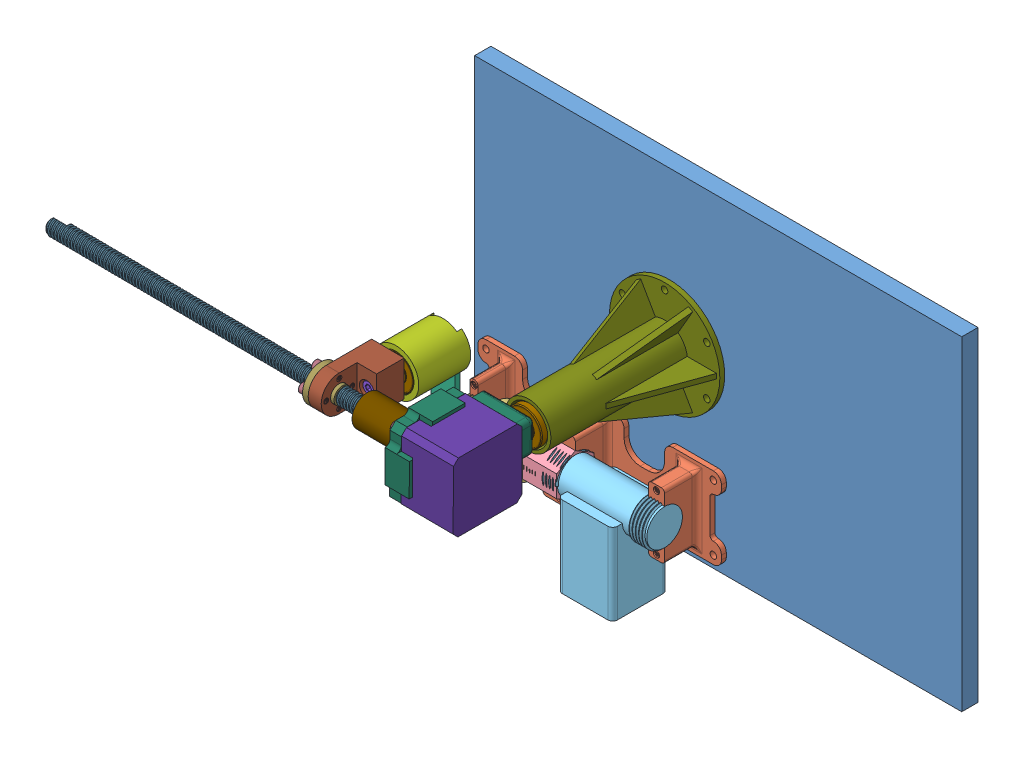
SolidWorks assembly ASM_gaz, configuration Défaut. Lengths in mm.
Overall size (432.05 220 163.25).
29 component instances, 18 part files, 83 mates.
Components (placement in the parent):
- socle-1: socle [Défaut] at (-258.099 -214.9208 295) size (300 200 10)
- support_gaz-1: support_gaz [Défaut] at (-178.099 -184.9208 305) size (150 50 23.02)
- valve-2: valve [Défaut] at (-186.099 -184.9208 328) x (0 1 0) z (0 0 1) size (30 53.36 57)
- raccord_male_male-1: raccord_male_male [Défaut] at (-194.099 -184.9208 328) x (0 -0.5 -0.866025) z (0 -0.866025 0.5) size (26.56 22.51 23)
- electro_vanne-1: electro_vanne [Défaut] at (-182.099 -184.9208 328) x (0 0 1) z (1 0 0) size (34 62.7 64.68)
- poignee_gaz-1: poignee_gaz [Défaut] at (-214.099 -193.9208 358) x (0 1 0) z (1 0 0) size (95 18 15)
- fix_poignee-1: fix_poignee [Défaut] at (-206.599 -107.9208 373) x (1 0 0) z (0 -1 0) size (28.2 32 28.2)
- M4_10-1: M4_10 [Défaut] at (-206.599 -107.9208 369) x (-0.866025 -0.5 0) z (-0.5 0.866025 0) size (7 14.03 7)
- roulement-1: roulement [Défaut] at (-206.599 -107.9208 401.5) x (0 0 -1) z (0.849779 -0.527139 0) size (7 22 22)
- axe_rlmnt-2: axe_rlmnt [Défaut] at (-206.599 -107.9208 396) x (-0.007299 -0.999973 0) z (-0.999973 0.007299 0) size (12 20 12)
- fix_ecrou-1: fix_ecrou [Défaut] at (-212.5988 -107.877 434) x (-0.007299 -0.999973 0) z (-0.999973 0.007299 0) size (22 39 20)
- ecrou_cuivre-1: ecrou_cuivre [Défaut] at (-225.5985 -107.7821 434) x (-0.007299 -0.999973 0) z (0 0 1) size (22 16.12 22)
- M3_10-1: M3_10 [Défaut] at (-227.04 -99.7713 434) x (-0.006321 -0.866002 0.5) z (0.00365 0.499987 0.866025) size (5.5 13 5.5)
- M3_10-2: M3_10 [Défaut] at (-227.0984 -107.7711 442) x (-0.006321 -0.866002 0.5) z (0.00365 0.499987 0.866025) size (5.5 13 5.5)
- M3_10-3: M3_10 [Défaut] at (-227.1568 -115.7709 434) x (-0.006321 -0.866002 0.5) z (0.00365 0.499987 0.866025) size (5.5 13 5.5)
- M3_10-4: M3_10 [Défaut] at (-227.0984 -107.7711 426) x (-0.006321 -0.866002 0.5) z (0.00365 0.499987 0.866025) size (5.5 13 5.5)
- Axe-1: Axe [Défaut] at (-390.0923 -106.5814 434) x (0.00546 0.747956 0.663725) z (0.004845 0.663708 -0.747976) size (9.68 200.01 11.13)
- fix_stepper-2: fix_stepper [Défaut] at (-160.0984 -108.2602 434) x (0.007299 0.999973 0) z (0.999973 -0.007299 0) size (48.5 62.5 30)
- axe_rlmnt-3: axe_rlmnt [Défaut] at (-138.099 -108.4208 385.75) x (-0.007299 -0.999973 0) z (-0.999973 0.007299 0) size (12 20 12)
- roulement-2: roulement [Défaut] at (-138.099 -108.4208 391.25) x (0 0 -1) z (1 -0.000497 0) size (7 22 22)
- M4_10-2: M4_10 [Défaut] at (-138.099 -108.4208 411.75) x (0.999973 -0.007299 0) z (0.007299 0.999973 0) size (7 14.03 7)
- support_stepper-1: support_stepper [Défaut] at (-138.099 -108.4208 305) x (1 0 0) z (0 -1 0) size (68 87 68)
- stepper_42-3: stepper_42 [Défaut] at (-121.0994 -108.5448 434) x (0 0 1) z (-0.999973 0.007299 0) size (42.3 42.3 56)
- M3_10-5: M3_10 [Défaut] at (-163.2114 -123.7379 418.5) x (-0.006321 -0.866002 -0.5) z (-0.00365 -0.499987 0.866025) size (5.5 13 5.5)
- M3_10-6: M3_10 [Défaut] at (-162.9852 -92.7387 418.5) x (-0.006321 -0.866002 -0.5) z (-0.00365 -0.499987 0.866025) size (5.5 13 5.5)
- M3_10-7: M3_10 [Défaut] at (-163.2114 -123.7379 449.5) x (-0.006321 -0.866002 -0.5) z (-0.00365 -0.499987 0.866025) size (5.5 13 5.5)
- M3_10-8: M3_10 [Défaut] at (-162.9852 -92.7387 449.5) x (-0.006321 -0.866002 -0.5) z (-0.00365 -0.499987 0.866025) size (5.5 13 5.5)
- connecteur_souple-2: connecteur_souple [Défaut] at (-195.0975 -108.0047 434) x (0.00546 0.747956 0.663725) z (0.004845 0.663708 -0.747976) size (19 25 19)
- M4_10-3: M4_10 [Défaut] at (-206.599 -107.9208 422) x (0.999973 -0.007299 0) z (0.007299 0.999973 0) size (7 14.03 7)
Mates (geometry in assembly coordinates):
- Coïncidente1: coincident anti-aligned: plane of socle-1 through (-258.099 -214.9208 305) normal (0 0 1); plane of support_gaz-1 through (-106.099 -206.9208 305) normal (0 0 -1)
- Distance1: distance = 5 mm aligned: plane of support_gaz-1 through (-106.099 -209.9208 308) normal (0 -1 0); plane of socle-1 through (-258.099 -214.9208 305) normal (0 -1 0)
- Distance2: distance = 5 mm aligned: plane of support_gaz-1 through (-253.099 -162.9208 308) normal (-1 0 0); plane of socle-1 through (-258.099 -214.9208 305) normal (-1 0 0)
- Coaxiale2: concentric aligned: cylinder of support_gaz-1 through (-203.4005 -184.9208 328) axis (-1 0 0) radius 10.5; cylinder of valve-2 through (-238.099 -184.9208 328) axis (-1 0 0) radius 15
- Coïncidente2: coincident aligned: plane of support_gaz-1 through (-238.099 -164.9208 328) normal (-1 0 0); plane of valve-2 through (-238.099 -195.4208 328) normal (-1 0 0)
- Parallèle1: parallel aligned: plane of socle-1 through (-258.099 -214.9208 305) normal (0 0 1); plane of valve-2 through (-206.599 -184.9208 358) normal (0 0 1)
- Coaxiale3: concentric: cylinder of valve-2 through (-238.7832 -184.9208 328) axis (1 0 0) radius 7; circle of raccord_male_male-1
- Coïncidente5: coincident anti-aligned: plane of valve-2 through (-194.099 -195.4208 328) normal (1 0 0); plane of raccord_male_male-1 through (-194.099 -184.9208 328) normal (-1 0 0)
- Parallèle2: parallel aligned: plane of socle-1 through (-258.099 -214.9208 305) normal (0 0 1); plane of raccord_male_male-1 through (-173.099 -178.2812 339.5) normal (0 0 1)
- Coaxiale4: concentric anti-aligned: cylinder of support_gaz-1 through (-157.7975 -184.9208 328) axis (1 0 0) radius 10.5; cylinder of electro_vanne-1 through (-118.099 -184.9208 328) axis (-1 0 0) radius 11
- Coïncidente8: coincident aligned: plane of support_gaz-1 through (-118.099 -164.9208 328) normal (1 0 0); plane of electro_vanne-1 through (-118.099 -184.9208 328) normal (1 0 0)
- Parallèle3: parallel aligned: plane of socle-1 through (-258.099 -214.9208 305) normal (0 -1 0); plane of electro_vanne-1 through (-136.099 -234.9208 342) normal (0 -1 0)
- Coaxiale5: concentric anti-aligned: cylinder of valve-2 through (-206.599 -184.9208 358) axis (0 0 -1) radius 7.5; cylinder of poignee_gaz-1 through (-206.599 -184.9208 358) axis (0 0 1) radius 4.5
- Coïncidente10: coincident anti-aligned: plane of valve-2 through (-206.599 -184.9208 358) normal (0 0 1); plane of poignee_gaz-1 through (-199.099 -193.9208 358) normal (0 0 -1)
- Coïncidente11: coincident anti-aligned: plane of poignee_gaz-1 through (-199.099 -98.9208 376) normal (0 0 1); plane of fix_poignee-1 through (-215.099 -93.8208 376) normal (0 0 -1)
- Coaxiale6: concentric aligned: cylinder of poignee_gaz-1 through (-206.599 -107.9208 358) axis (0 0 1) radius 3; cylinder of fix_poignee-1 through (-206.599 -107.9208 373) axis (0 0 1) radius 10.1
- Parallèle4: parallel anti-aligned: plane of poignee_gaz-1; plane of fix_poignee-1
- Coaxiale7: concentric aligned: cylinder of fix_poignee-1 through (-206.599 -107.9208 373) axis (0 0 1) radius 14.1; cylinder of M4_10-1 through (-206.599 -107.9208 383) axis (0 0 1) radius 3.5
- Coïncidente13: coincident anti-aligned: plane of poignee_gaz-1 through (-199.099 -153.9208 373) normal (0 0 -1); plane of M4_10-1 through (-203.5679 -106.1708 373) normal (0 0 1)
- Parallèle5: parallel aligned: plane of poignee_gaz-1 through (-199.099 -193.9208 358) normal (1 0 0); plane of M4_10-1 through (-208.099 -108.7868 371) normal (1 0 0)
- Coaxiale8: concentric anti-aligned: cylinder of fix_poignee-1 through (-206.599 -107.9208 373) axis (0 0 1) radius 11.1; cylinder of roulement-1 through (-206.599 -107.9208 401.5) axis (0 0 -1) radius 4
- Coïncidente15: coincident anti-aligned: plane of fix_poignee-1 through (-216.699 -107.9208 398) normal (0 0 1); plane of roulement-1 through (-201.064 -98.9981 398) normal (0 0 -1)
- Coaxiale9: concentric anti-aligned: cylinder of roulement-1 through (-206.599 -107.9208 401.5) axis (0 0 -1) radius 4; cylinder of axe_rlmnt-2 through (-206.599 -107.9208 398.5284) axis (0 0 1) radius 4
- Coïncidente16: coincident anti-aligned: plane of roulement-1 through (-201.064 -98.9981 398) normal (0 0 -1); plane of axe_rlmnt-2 through (-206.5552 -101.9209 398) normal (0 0 1)
- Coïncidente17: coincident anti-aligned: plane of fix_poignee-1 through (-216.699 -107.9208 398) normal (0 0 1); plane of roulement-1 through (-201.064 -98.9981 398) normal (0 0 -1)
- Coaxiale12: concentric anti-aligned: cylinder of axe_rlmnt-2 through (-206.599 -107.9208 398.5284) axis (0 0 1) radius 4; cylinder of fix_ecrou-1 through (-206.599 -107.9208 416) axis (0 0 -1) radius 4.25
- Coïncidente18: coincident anti-aligned: plane of axe_rlmnt-2 through (-209.5796 -105.2532 392.6148) normal (-0.999973 0.007299 0); plane of fix_ecrou-1 through (-209.5769 -104.8885 416) normal (0.999973 -0.007299 0)
- Coïncidente19: coincident anti-aligned: plane of axe_rlmnt-2 through (-206.5734 -104.4208 416) normal (0 0 1); plane of fix_ecrou-1 through (-206.599 -107.9208 416) normal (0 0 -1)
- Coaxiale13: concentric aligned: cylinder of fix_ecrou-1 through (-220.5986 -107.8186 434) axis (0.999973 -0.007299 0) radius 5.25; cylinder of ecrou_cuivre-1 through (-225.5985 -107.7821 434) axis (0.999973 -0.007299 0) radius 5.1
- Coïncidente20: coincident anti-aligned: plane of fix_ecrou-1 through (-220.5986 -107.8186 434) normal (-0.999973 0.007299 0); plane of ecrou_cuivre-1 through (-220.5183 -96.8189 434) normal (0.999973 -0.007299 0)
- Coaxiale14: concentric aligned: cone of fix_ecrou-1 through (-220.0986 -107.8222 442) axis (0.999973 -0.007299 0); cylinder of ecrou_cuivre-1 through (-225.5985 -107.7821 442) axis (0.999973 -0.007299 0) radius 1.75
- Coaxiale15: concentric aligned: cylinder of ecrou_cuivre-1 through (-225.5401 -99.7823 434) axis (0.999973 -0.007299 0) radius 1.75; cylinder of M3_10-1 through (-214.0404 -99.8662 434) axis (0.999973 -0.007299 0) radius 2.75
- Coïncidente21: coincident anti-aligned: plane of ecrou_cuivre-1 through (-224.0613 -102.6932 434) normal (-0.999973 0.007299 0); plane of M3_10-1 through (-224.0227 -97.4117 432.625) normal (0.999973 -0.007299 0)
- Parallèle6: parallel aligned: plane of fix_ecrou-1 through (-220.5183 -96.8189 434) normal (0.007299 0.999973 0); plane of M3_10-1 through (-225.0492 -101.0359 433.2783) normal (0.007299 0.999973 0)
- Coïncidente23: coincident anti-aligned: plane of ecrou_cuivre-1 through (-224.0613 -102.6932 434) normal (-0.999973 0.007299 0); plane of M3_10-2 through (-224.0811 -105.4115 440.625) normal (0.999973 -0.007299 0)
- Parallèle7: parallel aligned: plane of fix_ecrou-1 through (-220.5183 -96.8189 434) normal (0.007299 0.999973 0); plane of M3_10-2 through (-225.1076 -109.0357 441.2783) normal (0.007299 0.999973 0)
- Coaxiale16: concentric aligned: cylinder of ecrou_cuivre-1 through (-225.5985 -107.7821 442) axis (0.999973 -0.007299 0) radius 1.75; cylinder of M3_10-2 through (-214.0988 -107.866 442) axis (0.999973 -0.007299 0) radius 2.75
- Coïncidente24: coincident anti-aligned: plane of ecrou_cuivre-1 through (-224.0613 -102.6932 434) normal (-0.999973 0.007299 0); plane of M3_10-3 through (-224.1395 -113.4113 432.625) normal (0.999973 -0.007299 0)
- Parallèle8: parallel aligned: plane of fix_ecrou-1 through (-220.5183 -96.8189 434) normal (0.007299 0.999973 0); plane of M3_10-3 through (-225.166 -117.0355 433.2783) normal (0.007299 0.999973 0)
- Coaxiale17: concentric aligned: cylinder of ecrou_cuivre-1 through (-225.6569 -115.7819 434) axis (0.999973 -0.007299 0) radius 1.75; cylinder of M3_10-3 through (-214.1572 -115.8658 434) axis (0.999973 -0.007299 0) radius 2.75
- Coïncidente25: coincident anti-aligned: plane of ecrou_cuivre-1 through (-224.0613 -102.6932 434) normal (-0.999973 0.007299 0); plane of M3_10-4 through (-224.0811 -105.4115 424.625) normal (0.999973 -0.007299 0)
- Parallèle9: parallel aligned: plane of fix_ecrou-1 through (-220.5183 -96.8189 434) normal (0.007299 0.999973 0); plane of M3_10-4 through (-225.1076 -109.0357 425.2783) normal (0.007299 0.999973 0)
- Coaxiale18: concentric aligned: cylinder of ecrou_cuivre-1 through (-225.5985 -107.7821 426) axis (0.999973 -0.007299 0) radius 1.75; cylinder of M3_10-4 through (-214.0988 -107.866 426) axis (0.999973 -0.007299 0) radius 2.75
- Coaxiale19: concentric aligned: cylinder of ecrou_cuivre-1 through (-225.5985 -107.7821 434) axis (0.999973 -0.007299 0) radius 5.1; cone of Axe-1 through (-190.0976 -108.0412 434) axis (0.999973 -0.007299 0)
- Hélicoïdale1: screw = 1 mm anti-aligned: cylinder of ecrou_cuivre-1 through (-225.5985 -107.7821 434) axis (0.999973 -0.007299 0) radius 5.1; cone of Axe-1 through (-389.0923 -106.5887 434) axis (-0.999973 0.007299 0)
- Parallèle14: parallel anti-aligned: plane of socle-1 through (-258.099 -214.9208 305) normal (0 0 1); plane of fix_stepper-2 through (-130.0262 -98.4794 395.75) normal (0 0 -1)
- Coaxiale27: concentric aligned: cylinder of fix_stepper-2 through (-138.099 -108.4208 407.75) axis (0 0 1) radius 4.5; cylinder of axe_rlmnt-3 through (-138.099 -108.4208 388.2784) axis (0 0 1) radius 4
- Coïncidente32: coincident anti-aligned: plane of fix_stepper-2 through (-138.099 -108.4208 405.75) normal (0 0 -1); plane of axe_rlmnt-3 through (-138.0734 -104.9208 405.75) normal (0 0 1)
- Coïncidente33: coincident anti-aligned: plane of fix_stepper-2 through (-141.1209 -111.4092 405.75) normal (0.999973 -0.007299 0); plane of axe_rlmnt-3 through (-141.0796 -105.7532 382.3648) normal (-0.999973 0.007299 0)
- Coaxiale28: concentric anti-aligned: cylinder of axe_rlmnt-3 through (-138.099 -108.4208 388.2784) axis (0 0 1) radius 4; cylinder of roulement-2 through (-138.099 -108.4208 391.25) axis (0 0 -1) radius 4
- Coïncidente34: coincident anti-aligned: plane of axe_rlmnt-3 through (-138.0552 -102.4209 387.75) normal (0 0 1); plane of roulement-2 through (-138.096 -102.4208 387.75) normal (0 0 -1)
- Coaxiale29: concentric anti-aligned: cylinder of fix_stepper-2 through (-138.099 -108.4208 407.75) axis (0 0 1) radius 4.5; cylinder of M4_10-2 through (-138.099 -108.4208 397.75) axis (0 0 -1) radius 3.5
- Coïncidente35: coincident anti-aligned: plane of fix_stepper-2 through (-138.099 -108.4208 407.75) normal (0 0 1); plane of M4_10-2 through (-141.5989 -108.3952 407.75) normal (0 0 -1)
- Parallèle17: parallel aligned: plane of fix_stepper-2 through (-130.1722 -118.4789 412.75) normal (-0.007299 -0.999973 0); plane of M4_10-2 through (-137.222 -106.9271 409.75) normal (-0.007299 -0.999973 0)
- Coïncidente37: coincident anti-aligned: plane of socle-1 through (-258.099 -214.9208 305) normal (0 0 1); plane of support_stepper-1 through (-146.099 -108.4208 305) normal (0 0 -1)
- Coaxiale30: concentric anti-aligned: cylinder of roulement-2 through (-138.099 -108.4208 391.25) axis (0 0 -1) radius 11; cylinder of support_stepper-1 through (-138.099 -108.4208 310.7292) axis (0 0 1) radius 11
- Distance6: distance = 105 mm aligned: plane of support_stepper-1 through (-138.099 -109.9208 348.5) normal (0 -1 0); plane of socle-1 through (-258.099 -214.9208 305) normal (0 -1 0)
- Distance8: distance = 120 mm: cylinder of support_stepper-1 through (-138.099 -108.4208 310.7292) axis (0 0 1) radius 11; plane of socle-1 through (-258.099 -214.9208 305) normal (-1 0 0)
- Coaxiale31: concentric anti-aligned: cylinder of fix_stepper-2 through (-153.0986 -108.3113 434) axis (-0.999973 0.007299 0) radius 11.5; cylinder of stepper_42-3 through (-155.0985 -108.2967 434) axis (0.999973 -0.007299 0) radius 11
- Coaxiale32: concentric aligned: cylinder of fix_stepper-2 through (-153.2117 -123.8109 418.5) axis (-0.999973 0.007299 0) radius 1.75; cylinder of stepper_42-3 through (-143.212 -123.8838 418.5) axis (-0.999973 0.007299 0) radius 1.25
- Coïncidente40: coincident anti-aligned: plane of fix_stepper-2 through (-153.0986 -108.3113 434) normal (0.999973 -0.007299 0); plane of stepper_42-3 through (-153.0986 -108.3113 434) normal (-0.999973 0.007299 0)
- Coaxiale33: concentric anti-aligned: cylinder of fix_stepper-2 through (-153.2117 -123.8109 418.5) axis (-0.999973 0.007299 0) radius 1.75; cylinder of M3_10-5 through (-150.2118 -123.8328 418.5) axis (0.999973 -0.007299 0) radius 2.75
- Coïncidente41: coincident anti-aligned: plane of fix_stepper-2 through (-160.0984 -108.2602 434) normal (-0.999973 0.007299 0); plane of M3_10-5 through (-160.1941 -121.3783 419.875) normal (0.999973 -0.007299 0)
- Parallèle18: parallel aligned: plane of fix_stepper-2 through (-145.2758 -132.619 444) normal (-0.007299 -0.999973 0); plane of M3_10-5 through (-161.2024 -122.5025 419.2217) normal (-0.007299 -0.999973 0)
- Coïncidente43: coincident anti-aligned: plane of fix_stepper-2 through (-160.0984 -108.2602 434) normal (-0.999973 0.007299 0); plane of M3_10-6 through (-159.9679 -90.3791 419.875) normal (0.999973 -0.007299 0)
- Parallèle19: parallel aligned: plane of fix_stepper-2 through (-145.2758 -132.619 444) normal (-0.007299 -0.999973 0); plane of M3_10-6 through (-160.9761 -91.5033 419.2217) normal (-0.007299 -0.999973 0)
- Coaxiale34: concentric anti-aligned: cylinder of fix_stepper-2 through (-152.9854 -92.8117 418.5) axis (-0.999973 0.007299 0) radius 1.75; cylinder of M3_10-6 through (-149.9855 -92.8336 418.5) axis (0.999973 -0.007299 0) radius 2.75
- Coïncidente44: coincident anti-aligned: plane of fix_stepper-2 through (-160.0984 -108.2602 434) normal (-0.999973 0.007299 0); plane of M3_10-7 through (-160.1941 -121.3783 450.875) normal (0.999973 -0.007299 0)
- Parallèle20: parallel aligned: plane of fix_stepper-2 through (-145.2758 -132.619 444) normal (-0.007299 -0.999973 0); plane of M3_10-7 through (-161.2024 -122.5025 450.2217) normal (-0.007299 -0.999973 0)
- Coaxiale35: concentric anti-aligned: cylinder of fix_stepper-2 through (-153.2117 -123.8109 449.5) axis (-0.999973 0.007299 0) radius 1.75; cylinder of M3_10-7 through (-150.2118 -123.8328 449.5) axis (0.999973 -0.007299 0) radius 2.75
- Coïncidente45: coincident anti-aligned: plane of fix_stepper-2 through (-160.0984 -108.2602 434) normal (-0.999973 0.007299 0); plane of M3_10-8 through (-159.9679 -90.3791 450.875) normal (0.999973 -0.007299 0)
- Parallèle21: parallel aligned: plane of fix_stepper-2 through (-145.2758 -132.619 444) normal (-0.007299 -0.999973 0); plane of M3_10-8 through (-160.9761 -91.5033 450.2217) normal (-0.007299 -0.999973 0)
- Coaxiale36: concentric anti-aligned: cylinder of fix_stepper-2 through (-152.9854 -92.8117 449.5) axis (-0.999973 0.007299 0) radius 1.75; cylinder of M3_10-8 through (-149.9855 -92.8336 449.5) axis (0.999973 -0.007299 0) radius 2.75
- Coaxiale37: concentric aligned: cone of Axe-1 through (-190.0976 -108.0412 434) axis (0.999973 -0.007299 0); cylinder of connecteur_souple-2 through (-195.0975 -108.0047 434) axis (0.999973 -0.007299 0) radius 4
- Parallèle23: parallel aligned: plane of Axe-1; plane of connecteur_souple-2
- Coaxiale38: concentric aligned: cylinder of stepper_42-3 through (-177.0979 -108.1361 434) axis (0.999973 -0.007299 0) radius 2.5; cylinder of connecteur_souple-2 through (-195.0975 -108.0047 434) axis (0.999973 -0.007299 0) radius 2
- Parallèle24: parallel aligned: plane of Axe-1; plane of connecteur_souple-2
- Distance9: distance = 10 mm anti-aligned: plane of connecteur_souple-2 through (-170.109 -109.6831 432.6725) normal (0.999973 -0.007299 0); plane of fix_stepper-2 through (-160.0984 -108.2602 434) normal (-0.999973 0.007299 0)
- Distance10: distance = 5 mm anti-aligned: plane of connecteur_souple-2 through (-195.1493 -115.1103 427.6946) normal (-0.999973 0.007299 0); plane of Axe-1 through (-190.114 -110.2851 432.0088) normal (0.999973 -0.007299 0)
- AngleLimite1: limit planar angle = 0 rad anti-aligned: plane of poignee_gaz-1 through (-199.099 -193.9208 358) normal (1 0 0); plane of socle-1 through (-258.099 -214.9208 305) normal (-1 0 0)
- Coaxiale39: concentric anti-aligned: cylinder of fix_ecrou-1 through (-206.599 -107.9208 418) axis (0 0 1) radius 4.5; cylinder of M4_10-3 through (-206.599 -107.9208 408) axis (0 0 -1) radius 3.5
- Coïncidente52: coincident anti-aligned: plane of fix_ecrou-1 through (-206.599 -107.9208 418) normal (0 0 1); plane of M4_10-3 through (-210.0989 -107.8952 418) normal (0 0 -1)
- Parallèle26: parallel aligned: plane of fix_ecrou-1 through (-220.6789 -118.8183 406) normal (-0.007299 -0.999973 0); plane of M4_10-3 through (-205.722 -106.4271 420) normal (-0.007299 -0.999973 0)
